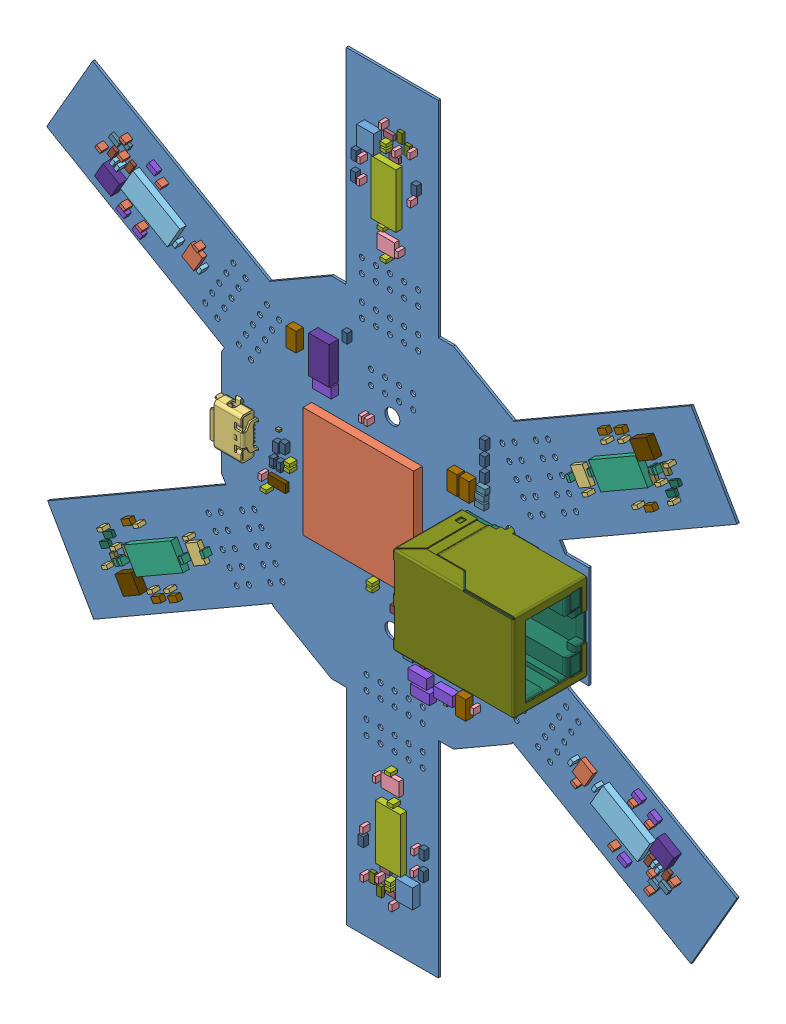
SolidWorks assembly PCB_Testplatine, configuration Standard. Lengths in mm.
Overall size (124.77 137.35 16.55).
543 component instances, 40 part files, 0 mates.
Components (placement in the parent):
- Board-1: Board [Standard] at (0 0 -0.4115) size (124.77 137.35 0.41)
- X_TDA_1_TDA6-1: X_TDA_1_TDA6 [Standard] at origin size (3.77 4.02 0.8)
  - 668293800-1: 668293800 [Standard] at (-35.3942 22.6879 0) size (3.77 4.02 0.8)
    - Extruded-1: Extruded [Standard] at origin size (3.77 4.02 0.8)
- X_TDA_1_TDA5-1: X_TDA_1_TDA5 [Standard] at origin size (3.77 4.02 0.8)
  - 668293664-1: 668293664 [Standard] at (-34.8042 -23.4933 0) size (3.77 4.02 0.8)
    - Extruded_2-1: Extruded_2 [Standard] at origin size (3.77 4.02 0.8)
- X_TDA_1_TDA4-1: X_TDA_1_TDA4 [Standard] at origin size (3.2 2.5 0.8)
  - 668292848-1: 668292848 [Standard] at (0.38 -41.99 0) size (3.2 2.5 0.8)
    - Extruded_3-1: Extruded_3 [Standard] at origin size (3.2 2.5 0.8)
- X_TDA_1_TDA3-1: X_TDA_1_TDA3 [Standard] at origin size (3.77 4.02 0.8)
  - 668293800-1: 668293800 [Standard] at (35.1741 -22.7679 0) size (3.77 4.02 0.8)
    - Extruded-1: Extruded [Standard] at origin size (3.77 4.02 0.8)
- X_TDA_1_TDA2-1: X_TDA_1_TDA2 [Standard] at origin size (3.77 4.02 0.8)
  - 668293664-1: 668293664 [Standard] at (34.8045 23.5121 0) size (3.77 4.02 0.8)
    - Extruded_2-1: Extruded_2 [Standard] at origin size (3.77 4.02 0.8)
- TDA5340_TDA6-1: TDA5340_TDA6 [Standard] at origin size (10.74 8.8 1.15)
  - 668292576-1: 668292576 [Standard] at (-42.5822 26.8379 0.05) size (10.74 8.8 1.15)
    - Extruded_4-1: Extruded_4 [Standard] at origin size (10.74 8.8 1.15)
- TDA5340_TDA5-1: TDA5340_TDA5 [Standard] at origin size (10.74 8.8 1.15)
  - 668292440-1: 668292440 [Standard] at (-41.9922 -27.6432 0.05) size (10.74 8.8 1.15)
    - Extruded_5-1: Extruded_5 [Standard] at origin size (10.74 8.8 1.15)
- TDA5340_TDA4-1: TDA5340_TDA4 [Standard] at origin size (4.5 9.8 1.15)
  - 668289992-1: 668289992 [Standard] at (0.38 -50.29 0.05) size (4.5 9.8 1.15)
    - Extruded_6-1: Extruded_6 [Standard] at origin size (4.5 9.8 1.15)
- TDA5340_TDA3-1: TDA5340_TDA3 [Standard] at origin size (10.74 8.8 1.15)
  - 668292576-1: 668292576 [Standard] at (42.3622 -26.9179 0.05) size (10.74 8.8 1.15)
    - Extruded_4-1: Extruded_4 [Standard] at origin size (10.74 8.8 1.15)
- TDA5340_TDA2-1: TDA5340_TDA2 [Standard] at origin size (10.74 8.8 1.15)
  - 668292440-1: 668292440 [Standard] at (41.9925 27.6621 0.05) size (10.74 8.8 1.15)
    - Extruded_5-1: Extruded_5 [Standard] at origin size (10.74 8.8 1.15)
- R3_TDA6-1: R3_TDA6 [Standard] at origin size (1.95 1.67 0.9)
  - 668292304-1: 668292304 [Standard] at (-42.6285 32.8576 0) size (1.95 1.67 0.9)
    - Extruded_7-1: Extruded_7 [Standard] at origin size (1.95 1.67 0.9)
- R3_TDA5-1: R3_TDA5 [Standard] at origin size (1.95 1.67 0.9)
  - 668292168-1: 668292168 [Standard] at (-47.2285 -24.6736 0) size (1.95 1.67 0.9)
    - Extruded_8-1: Extruded_8 [Standard] at origin size (1.95 1.67 0.9)
- R3_TDA4-1: R3_TDA4 [Standard] at origin size (0.95 1.7 0.9)
  - 668289312-1: 668289312 [Standard] at (-4.81 -53.34 0) size (0.95 1.7 0.9)
    - Extruded_9-1: Extruded_9 [Standard] at origin size (0.95 1.7 0.9)
- R3_TDA3-1: R3_TDA3 [Standard] at origin size (1.95 1.67 0.9)
  - 668292304-1: 668292304 [Standard] at (42.4085 -32.9376 0) size (1.95 1.67 0.9)
    - Extruded_7-1: Extruded_7 [Standard] at origin size (1.95 1.67 0.9)
- R3_TDA2-1: R3_TDA2 [Standard] at origin size (1.95 1.67 0.9)
  - 668292168-1: 668292168 [Standard] at (47.2288 24.6924 0) size (1.95 1.67 0.9)
    - Extruded_8-1: Extruded_8 [Standard] at origin size (1.95 1.67 0.9)
- R2_TDA6-1: R2_TDA6 [Standard] at origin size (1.95 1.67 0.9)
  - 668292304-1: 668292304 [Standard] at (-48.1169 23.4516 0) size (1.95 1.67 0.9)
    - Extruded_7-1: Extruded_7 [Standard] at origin size (1.95 1.67 0.9)
- R2_TDA5-1: R2_TDA5 [Standard] at origin size (1.95 1.67 0.9)
  - 668292168-1: 668292168 [Standard] at (-41.8269 -34.1296 0) size (1.95 1.67 0.9)
    - Extruded_8-1: Extruded_8 [Standard] at origin size (1.95 1.67 0.9)
- R2_TDA4-1: R2_TDA4 [Standard] at origin size (0.95 1.7 0.9)
  - 668289312-1: 668289312 [Standard] at (6.08 -53.39 0) size (0.95 1.7 0.9)
    - Extruded_9-1: Extruded_9 [Standard] at origin size (0.95 1.7 0.9)
- R2_TDA3-1: R2_TDA3 [Standard] at origin size (1.95 1.67 0.9)
  - 668292304-1: 668292304 [Standard] at (47.8969 -23.5316 0) size (1.95 1.67 0.9)
    - Extruded_7-1: Extruded_7 [Standard] at origin size (1.95 1.67 0.9)
- R2_TDA2-1: R2_TDA2 [Standard] at origin size (1.95 1.67 0.9)
  - 668292168-1: 668292168 [Standard] at (41.8271 34.1484 0) size (1.95 1.67 0.9)
    - Extruded_8-1: Extruded_8 [Standard] at origin size (1.95 1.67 0.9)
- R1_TDA6-1: R1_TDA6 [Standard] at origin size (1.95 1.67 0.9)
  - 668292304-1: 668292304 [Standard] at (-45.2224 21.6649 0) size (1.95 1.67 0.9)
    - Extruded_7-1: Extruded_7 [Standard] at origin size (1.95 1.67 0.9)
- R1_TDA5-1: R1_TDA5 [Standard] at origin size (1.95 1.67 0.9)
  - 668292168-1: 668292168 [Standard] at (-38.8324 -32.5162 0) size (1.95 1.67 0.9)
    - Extruded_8-1: Extruded_8 [Standard] at origin size (1.95 1.67 0.9)
- R1_TDA4-1: R1_TDA4 [Standard] at origin size (0.95 1.7 0.9)
  - 668289312-1: 668289312 [Standard] at (6.18 -49.99 0) size (0.95 1.7 0.9)
    - Extruded_9-1: Extruded_9 [Standard] at origin size (0.95 1.7 0.9)
- R1_TDA3-1: R1_TDA3 [Standard] at origin size (1.95 1.67 0.9)
  - 668292304-1: 668292304 [Standard] at (45.0024 -21.7449 0) size (1.95 1.67 0.9)
    - Extruded_7-1: Extruded_7 [Standard] at origin size (1.95 1.67 0.9)
- R1_TDA2-1: R1_TDA2 [Standard] at origin size (1.95 1.67 0.9)
  - 668292168-1: 668292168 [Standard] at (38.8326 32.535 0) size (1.95 1.67 0.9)
    - Extruded_8-1: Extruded_8 [Standard] at origin size (1.95 1.67 0.9)
- L4_TDA6-1: L4_TDA6 [Standard] at origin size (1.7 1.99 0.55)
  - 668291760-1: 668291760 [Standard] at (-50.1898 31.4611 0) size (1.7 1.99 0.55)
    - Extruded_10-1: Extruded_10 [Standard] at origin size (1.7 1.99 0.55)
- L4_TDA5-1: L4_TDA5 [Standard] at origin size (1.7 1.99 0.55)
  - 668291624-1: 668291624 [Standard] at (-49.7998 -31.9201 0) size (1.7 1.99 0.55)
    - Extruded_11-1: Extruded_11 [Standard] at origin size (1.7 1.99 0.55)
- L4_TDA4-1: L4_TDA4 [Standard] at origin size (1.75 0.95 0.55)
  - 668290400-1: 668290400 [Standard] at (0.18 -59.19 0) size (1.75 0.95 0.55)
    - Extruded_12-1: Extruded_12 [Standard] at origin size (1.75 0.95 0.55)
- L4_TDA3-1: L4_TDA3 [Standard] at origin size (1.7 1.99 0.55)
  - 668291760-1: 668291760 [Standard] at (49.9698 -31.5411 0) size (1.7 1.99 0.55)
    - Extruded_10-1: Extruded_10 [Standard] at origin size (1.7 1.99 0.55)
- L4_TDA2-1: L4_TDA2 [Standard] at origin size (1.7 1.99 0.55)
  - 668291624-1: 668291624 [Standard] at (49.8001 31.9389 0) size (1.7 1.99 0.55)
    - Extruded_11-1: Extruded_11 [Standard] at origin size (1.7 1.99 0.55)
- L3_TDA6-1: L3_TDA6 [Standard] at origin size (1.99 1.7 0.55)
  - 668292032-1: 668292032 [Standard] at (-47.8899 34.0246 0) size (1.99 1.7 0.55)
    - Extruded_13-1: Extruded_13 [Standard] at origin size (1.99 1.7 0.55)
- L3_TDA5-1: L3_TDA5 [Standard] at origin size (1.99 1.7 0.55)
  - 668291896-1: 668291896 [Standard] at (-50.8699 -28.6466 0) size (1.99 1.7 0.55)
    - Extruded_14-1: Extruded_14 [Standard] at origin size (1.99 1.7 0.55)
- L3_TDA4-1: L3_TDA4 [Standard] at origin size (0.95 1.75 0.55)
  - 668290536-1: 668290536 [Standard] at (-3.19 -58.48 0) size (0.95 1.75 0.55)
    - Extruded_15-1: Extruded_15 [Standard] at origin size (0.95 1.75 0.55)
- L3_TDA3-1: L3_TDA3 [Standard] at origin size (1.99 1.7 0.55)
  - 668292032-1: 668292032 [Standard] at (47.6699 -34.1046 0) size (1.99 1.7 0.55)
    - Extruded_13-1: Extruded_13 [Standard] at origin size (1.99 1.7 0.55)
- L3_TDA2-1: L3_TDA2 [Standard] at origin size (1.99 1.7 0.55)
  - 668291896-1: 668291896 [Standard] at (50.8702 28.6654 0) size (1.99 1.7 0.55)
    - Extruded_14-1: Extruded_14 [Standard] at origin size (1.99 1.7 0.55)
- L2_TDA6-1: L2_TDA6 [Standard] at origin size (1.99 1.7 0.55)
  - 668292032-1: 668292032 [Standard] at (-49.792 33.6101 0) size (1.99 1.7 0.55)
    - Extruded_13-1: Extruded_13 [Standard] at origin size (1.99 1.7 0.55)
- L2_TDA5-1: L2_TDA5 [Standard] at origin size (1.99 1.7 0.55)
  - 668291896-1: 668291896 [Standard] at (-51.462 -30.5011 0) size (1.99 1.7 0.55)
    - Extruded_14-1: Extruded_14 [Standard] at origin size (1.99 1.7 0.55)
- L2_TDA4-1: L2_TDA4 [Standard] at origin size (0.95 1.75 0.55)
  - 668290536-1: 668290536 [Standard] at (-1.88 -59.92 0) size (0.95 1.75 0.55)
    - Extruded_15-1: Extruded_15 [Standard] at origin size (0.95 1.75 0.55)
- L2_TDA3-1: L2_TDA3 [Standard] at origin size (1.99 1.7 0.55)
  - 668292032-1: 668292032 [Standard] at (49.572 -33.6901 0) size (1.99 1.7 0.55)
    - Extruded_13-1: Extruded_13 [Standard] at origin size (1.99 1.7 0.55)
- L2_TDA2-1: L2_TDA2 [Standard] at origin size (1.99 1.7 0.55)
  - 668291896-1: 668291896 [Standard] at (51.4623 30.5199 0) size (1.99 1.7 0.55)
    - Extruded_14-1: Extruded_14 [Standard] at origin size (1.99 1.7 0.55)
- L1_TDA6-1: L1_TDA6 [Standard] at origin size (1.7 1.99 0.55)
  - 668291760-1: 668291760 [Standard] at (-47.0051 30.7771 0) size (1.7 1.99 0.55)
    - Extruded_10-1: Extruded_10 [Standard] at origin size (1.7 1.99 0.55)
- L1_TDA5-1: L1_TDA5 [Standard] at origin size (1.7 1.99 0.55)
  - 668291624-1: 668291624 [Standard] at (-47.6151 -29.504 0) size (1.7 1.99 0.55)
    - Extruded_11-1: Extruded_11 [Standard] at origin size (1.7 1.99 0.55)
- L1_TDA4-1: L1_TDA4 [Standard] at origin size (1.75 0.95 0.55)
  - 668290400-1: 668290400 [Standard] at (-0.82 -56.09 0) size (1.75 0.95 0.55)
    - Extruded_12-1: Extruded_12 [Standard] at origin size (1.75 0.95 0.55)
- L1_TDA3-1: L1_TDA3 [Standard] at origin size (1.7 1.99 0.55)
  - 668291760-1: 668291760 [Standard] at (46.7851 -30.8571 0) size (1.7 1.99 0.55)
    - Extruded_10-1: Extruded_10 [Standard] at origin size (1.7 1.99 0.55)
- L1_TDA2-1: L1_TDA2 [Standard] at origin size (1.7 1.99 0.55)
  - 668291624-1: 668291624 [Standard] at (47.6154 29.5229 0) size (1.7 1.99 0.55)
    - Extruded_11-1: Extruded_11 [Standard] at origin size (1.7 1.99 0.55)
- F1_TDA6-1: F1_TDA6 [Standard] at origin size (4.54 4.41 1.4)
  - 668293528-1: 668293528 [Standard] at (-50.1943 27.6532 0) size (4.54 4.41 1.4)
    - Extruded_16-1: Extruded_16 [Standard] at origin size (4.54 4.41 1.4)
- F1_TDA5-1: F1_TDA5 [Standard] at origin size (4.54 4.41 1.4)
  - 668293392-1: 668293392 [Standard] at (-46.5044 -33.8279 0) size (4.54 4.41 1.4)
    - Extruded_17-1: Extruded_17 [Standard] at origin size (4.54 4.41 1.4)
- F1_TDA4-1: F1_TDA4 [Standard] at origin size (3.1 3.45 1.4)
  - 668293256-1: 668293256 [Standard] at (3.48 -57.29 0) size (3.1 3.45 1.4)
    - Extruded_18-1: Extruded_18 [Standard] at origin size (3.1 3.45 1.4)
- F1_TDA3-1: F1_TDA3 [Standard] at origin size (4.54 4.41 1.4)
  - 668293528-1: 668293528 [Standard] at (49.9743 -27.7332 0) size (4.54 4.41 1.4)
    - Extruded_16-1: Extruded_16 [Standard] at origin size (4.54 4.41 1.4)
- F1_TDA2-1: F1_TDA2 [Standard] at origin size (4.54 4.41 1.4)
  - 668293392-1: 668293392 [Standard] at (46.5047 33.8467 0) size (4.54 4.41 1.4)
    - Extruded_17-1: Extruded_17 [Standard] at origin size (4.54 4.41 1.4)
- C31_TDA6-1: C31_TDA6 [Standard] at origin size (1.25 1.07 1.3)
  - 668291216-1: 668291216 [Standard] at (-51.8712 31.5889 0) size (1.25 1.07 1.3)
    - Extruded_19-1: Extruded_19 [Standard] at origin size (1.25 1.07 1.3)
- C31_TDA5-1: C31_TDA5 [Standard] at origin size (1.25 1.07 1.3)
  - 668291080-1: 668291080 [Standard] at (-50.7512 -33.3123 0) size (1.25 1.07 1.3)
    - Extruded_20-1: Extruded_20 [Standard] at origin size (1.25 1.07 1.3)
- C31_TDA4-1: C31_TDA4 [Standard] at origin size (0.6 1.1 1.3)
  - 668289448-1: 668289448 [Standard] at (0.91 -60.71 0) size (0.6 1.1 1.3)
    - Extruded_21-1: Extruded_21 [Standard] at origin size (0.6 1.1 1.3)
- C31_TDA3-1: C31_TDA3 [Standard] at origin size (1.25 1.07 1.3)
  - 668291216-1: 668291216 [Standard] at (51.6512 -31.6689 0) size (1.25 1.07 1.3)
    - Extruded_19-1: Extruded_19 [Standard] at origin size (1.25 1.07 1.3)
- C31_TDA2-1: C31_TDA2 [Standard] at origin size (1.25 1.07 1.3)
  - 668291080-1: 668291080 [Standard] at (50.7515 33.3311 0) size (1.25 1.07 1.3)
    - Extruded_20-1: Extruded_20 [Standard] at origin size (1.25 1.07 1.3)
- C30_TDA6-1: C30_TDA6 [Standard] at origin size (1.25 1.07 1.3)
  - 668291216-1: 668291216 [Standard] at (-47.5295 35.0289 0) size (1.25 1.07 1.3)
    - Extruded_19-1: Extruded_19 [Standard] at origin size (1.25 1.07 1.3)
- C30_TDA5-1: C30_TDA5 [Standard] at origin size (1.25 1.07 1.3)
  - 668291080-1: 668291080 [Standard] at (-51.5595 -27.8323 0) size (1.25 1.07 1.3)
    - Extruded_20-1: Extruded_20 [Standard] at origin size (1.25 1.07 1.3)
- C30_TDA4-1: C30_TDA4 [Standard] at origin size (0.6 1.1 1.3)
  - 668289448-1: 668289448 [Standard] at (-4.24 -58.67 0) size (0.6 1.1 1.3)
    - Extruded_21-1: Extruded_21 [Standard] at origin size (0.6 1.1 1.3)
- C30_TDA3-1: C30_TDA3 [Standard] at origin size (1.25 1.07 1.3)
  - 668291216-1: 668291216 [Standard] at (47.3095 -35.1089 0) size (1.25 1.07 1.3)
    - Extruded_19-1: Extruded_19 [Standard] at origin size (1.25 1.07 1.3)
- C30_TDA2-1: C30_TDA2 [Standard] at origin size (1.25 1.07 1.3)
  - 668291080-1: 668291080 [Standard] at (51.5598 27.8511 0) size (1.25 1.07 1.3)
    - Extruded_20-1: Extruded_20 [Standard] at origin size (1.25 1.07 1.3)
- C29_TDA6-1: C29_TDA6 [Standard] at origin size (1.07 1.25 1.3)
  - 668291488-1: 668291488 [Standard] at (-49.3371 30.7379 0) size (1.07 1.25 1.3)
    - Extruded_22-1: Extruded_22 [Standard] at origin size (1.07 1.25 1.3)
- C29_TDA5-1: C29_TDA5 [Standard] at origin size (1.07 1.25 1.3)
  - 668291352-1: 668291352 [Standard] at (-48.7472 -31.5432 0) size (1.07 1.25 1.3)
    - Extruded_23-1: Extruded_23 [Standard] at origin size (1.07 1.25 1.3)
- C29_TDA4-1: C29_TDA4 [Standard] at origin size (1.1 0.6 1.3)
  - 668289176-1: 668289176 [Standard] at (0.38 -58.09 0) size (1.1 0.6 1.3)
    - Extruded_24-1: Extruded_24 [Standard] at origin size (1.1 0.6 1.3)
- C29_TDA3-1: C29_TDA3 [Standard] at origin size (1.07 1.25 1.3)
  - 668291488-1: 668291488 [Standard] at (49.1171 -30.8179 0) size (1.07 1.25 1.3)
    - Extruded_22-1: Extruded_22 [Standard] at origin size (1.07 1.25 1.3)
- C29_TDA2-1: C29_TDA2 [Standard] at origin size (1.07 1.25 1.3)
  - 668291352-1: 668291352 [Standard] at (48.7475 31.5621 0) size (1.07 1.25 1.3)
    - Extruded_23-1: Extruded_23 [Standard] at origin size (1.07 1.25 1.3)
- C28_TDA6-1: C28_TDA6 [Standard] at origin size (1.07 1.25 1.3)
  - 668291488-1: 668291488 [Standard] at (-48.5577 30.2879 0) size (1.07 1.25 1.3)
    - Extruded_22-1: Extruded_22 [Standard] at origin size (1.07 1.25 1.3)
- C28_TDA5-1: C28_TDA5 [Standard] at origin size (1.07 1.25 1.3)
  - 668291352-1: 668291352 [Standard] at (-47.9677 -31.0933 0) size (1.07 1.25 1.3)
    - Extruded_23-1: Extruded_23 [Standard] at origin size (1.07 1.25 1.3)
- C28_TDA4-1: C28_TDA4 [Standard] at origin size (1.1 0.6 1.3)
  - 668289176-1: 668289176 [Standard] at (0.38 -57.19 0) size (1.1 0.6 1.3)
    - Extruded_24-1: Extruded_24 [Standard] at origin size (1.1 0.6 1.3)
- C28_TDA3-1: C28_TDA3 [Standard] at origin size (1.07 1.25 1.3)
  - 668291488-1: 668291488 [Standard] at (48.3377 -30.3679 0) size (1.07 1.25 1.3)
    - Extruded_22-1: Extruded_22 [Standard] at origin size (1.07 1.25 1.3)
- C28_TDA2-1: C28_TDA2 [Standard] at origin size (1.07 1.25 1.3)
  - 668291352-1: 668291352 [Standard] at (47.968 31.1121 0) size (1.07 1.25 1.3)
    - Extruded_23-1: Extruded_23 [Standard] at origin size (1.07 1.25 1.3)
- C27_TDA6-1: C27_TDA6 [Standard] at origin size (1.25 1.07 1.3)
  - 668291216-1: 668291216 [Standard] at (-47.9541 32.1333 0) size (1.25 1.07 1.3)
    - Extruded_19-1: Extruded_19 [Standard] at origin size (1.25 1.07 1.3)
- C27_TDA5-1: C27_TDA5 [Standard] at origin size (1.25 1.07 1.3)
  - 668291080-1: 668291080 [Standard] at (-49.2641 -29.6478 0) size (1.25 1.07 1.3)
    - Extruded_20-1: Extruded_20 [Standard] at origin size (1.25 1.07 1.3)
- C27_TDA4-1: C27_TDA4 [Standard] at origin size (0.6 1.1 1.3)
  - 668289448-1: 668289448 [Standard] at (-1.52 -57.59 0) size (0.6 1.1 1.3)
    - Extruded_21-1: Extruded_21 [Standard] at origin size (0.6 1.1 1.3)
- C27_TDA3-1: C27_TDA3 [Standard] at origin size (1.25 1.07 1.3)
  - 668291216-1: 668291216 [Standard] at (47.7341 -32.2133 0) size (1.25 1.07 1.3)
    - Extruded_19-1: Extruded_19 [Standard] at origin size (1.25 1.07 1.3)
- C27_TDA2-1: C27_TDA2 [Standard] at origin size (1.25 1.07 1.3)
  - 668291080-1: 668291080 [Standard] at (49.2644 29.6666 0) size (1.25 1.07 1.3)
    - Extruded_20-1: Extruded_20 [Standard] at origin size (1.25 1.07 1.3)
- C26_TDA6-1: C26_TDA6 [Standard] at origin size (1.07 1.25 1.3)
  - 668291488-1: 668291488 [Standard] at (-33.6621 21.6879 0) size (1.07 1.25 1.3)
    - Extruded_22-1: Extruded_22 [Standard] at origin size (1.07 1.25 1.3)
- C26_TDA5-1: C26_TDA5 [Standard] at origin size (1.07 1.25 1.3)
  - 668291352-1: 668291352 [Standard] at (-33.0721 -22.4933 0) size (1.07 1.25 1.3)
    - Extruded_23-1: Extruded_23 [Standard] at origin size (1.07 1.25 1.3)
- C26_TDA4-1: C26_TDA4 [Standard] at origin size (1.1 0.6 1.3)
  - 668289176-1: 668289176 [Standard] at (0.38 -39.99 0) size (1.1 0.6 1.3)
    - Extruded_24-1: Extruded_24 [Standard] at origin size (1.1 0.6 1.3)
- C26_TDA3-1: C26_TDA3 [Standard] at origin size (1.07 1.25 1.3)
  - 668291488-1: 668291488 [Standard] at (33.4421 -21.7679 0) size (1.07 1.25 1.3)
    - Extruded_22-1: Extruded_22 [Standard] at origin size (1.07 1.25 1.3)
- C26_TDA2-1: C26_TDA2 [Standard] at origin size (1.07 1.25 1.3)
  - 668291352-1: 668291352 [Standard] at (33.0724 22.5121 0) size (1.07 1.25 1.3)
    - Extruded_23-1: Extruded_23 [Standard] at origin size (1.07 1.25 1.3)
- C25_TDA6-1: C25_TDA6 [Standard] at origin size (1.25 1.07 1.3)
  - 668291216-1: 668291216 [Standard] at (-34.2808 24.8163 0) size (1.25 1.07 1.3)
    - Extruded_19-1: Extruded_19 [Standard] at origin size (1.25 1.07 1.3)
- C25_TDA5-1: C25_TDA5 [Standard] at origin size (1.25 1.07 1.3)
  - 668291080-1: 668291080 [Standard] at (-36.0907 -21.4648 0) size (1.25 1.07 1.3)
    - Extruded_20-1: Extruded_20 [Standard] at origin size (1.25 1.07 1.3)
- C25_TDA4-1: C25_TDA4 [Standard] at origin size (0.6 1.1 1.3)
  - 668289448-1: 668289448 [Standard] at (-2.02 -42.09 0) size (0.6 1.1 1.3)
    - Extruded_21-1: Extruded_21 [Standard] at origin size (0.6 1.1 1.3)
- C25_TDA3-1: C25_TDA3 [Standard] at origin size (1.25 1.07 1.3)
  - 668291216-1: 668291216 [Standard] at (34.0607 -24.8964 0) size (1.25 1.07 1.3)
    - Extruded_19-1: Extruded_19 [Standard] at origin size (1.25 1.07 1.3)
- C25_TDA2-1: C25_TDA2 [Standard] at origin size (1.25 1.07 1.3)
  - 668291080-1: 668291080 [Standard] at (36.091 21.4836 0) size (1.25 1.07 1.3)
    - Extruded_20-1: Extruded_20 [Standard] at origin size (1.25 1.07 1.3)
- C24_TDA6-1: C24_TDA6 [Standard] at origin size (1.07 1.25 1.3)
  - 668291488-1: 668291488 [Standard] at (-37.9824 23.6049 0) size (1.07 1.25 1.3)
    - Extruded_22-1: Extruded_22 [Standard] at origin size (1.07 1.25 1.3)
- C24_TDA5-1: C24_TDA5 [Standard] at origin size (1.07 1.25 1.3)
  - 668291352-1: 668291352 [Standard] at (-36.8924 -25.2763 0) size (1.07 1.25 1.3)
    - Extruded_23-1: Extruded_23 [Standard] at origin size (1.07 1.25 1.3)
- C24_TDA4-1: C24_TDA4 [Standard] at origin size (1.1 0.6 1.3)
  - 668289176-1: 668289176 [Standard] at (0.88 -44.69 0) size (1.1 0.6 1.3)
    - Extruded_24-1: Extruded_24 [Standard] at origin size (1.1 0.6 1.3)
- C24_TDA3-1: C24_TDA3 [Standard] at origin size (1.07 1.25 1.3)
  - 668291488-1: 668291488 [Standard] at (37.7624 -23.6849 0) size (1.07 1.25 1.3)
    - Extruded_22-1: Extruded_22 [Standard] at origin size (1.07 1.25 1.3)
- C24_TDA2-1: C24_TDA2 [Standard] at origin size (1.07 1.25 1.3)
  - 668291352-1: 668291352 [Standard] at (36.8927 25.2951 0) size (1.07 1.25 1.3)
    - Extruded_23-1: Extruded_23 [Standard] at origin size (1.07 1.25 1.3)
- C23_TDA6-1: C23_TDA6 [Standard] at origin size (1.25 1.07 1.3)
  - 668291216-1: 668291216 [Standard] at (-41.0166 31.3495 0) size (1.25 1.07 1.3)
    - Extruded_19-1: Extruded_19 [Standard] at origin size (1.25 1.07 1.3)
- C23_TDA5-1: C23_TDA5 [Standard] at origin size (1.25 1.07 1.3)
  - 668291080-1: 668291080 [Standard] at (-45.1166 -24.0316 0) size (1.25 1.07 1.3)
    - Extruded_20-1: Extruded_20 [Standard] at origin size (1.25 1.07 1.3)
- C23_TDA4-1: C23_TDA4 [Standard] at origin size (0.6 1.1 1.3)
  - 668289448-1: 668289448 [Standard] at (-4.31 -51.19 0) size (0.6 1.1 1.3)
    - Extruded_21-1: Extruded_21 [Standard] at origin size (0.6 1.1 1.3)
- C23_TDA3-1: C23_TDA3 [Standard] at origin size (1.25 1.07 1.3)
  - 668291216-1: 668291216 [Standard] at (40.7966 -31.4296 0) size (1.25 1.07 1.3)
    - Extruded_19-1: Extruded_19 [Standard] at origin size (1.25 1.07 1.3)
- C23_TDA2-1: C23_TDA2 [Standard] at origin size (1.25 1.07 1.3)
  - 668291080-1: 668291080 [Standard] at (45.1169 24.0504 0) size (1.25 1.07 1.3)
    - Extruded_20-1: Extruded_20 [Standard] at origin size (1.25 1.07 1.3)
- C22_TDA6-1: C22_TDA6 [Standard] at origin size (1.25 1.07 1.3)
  - 668291216-1: 668291216 [Standard] at (-47.5534 24.6274 0) size (1.25 1.07 1.3)
    - Extruded_19-1: Extruded_19 [Standard] at origin size (1.25 1.07 1.3)
- C22_TDA5-1: C22_TDA5 [Standard] at origin size (1.25 1.07 1.3)
  - 668291080-1: 668291080 [Standard] at (-42.5634 -33.0538 0) size (1.25 1.07 1.3)
    - Extruded_20-1: Extruded_20 [Standard] at origin size (1.25 1.07 1.3)
- C22_TDA4-1: C22_TDA4 [Standard] at origin size (0.6 1.1 1.3)
  - 668289448-1: 668289448 [Standard] at (4.78 -53.49 0) size (0.6 1.1 1.3)
    - Extruded_21-1: Extruded_21 [Standard] at origin size (0.6 1.1 1.3)
- C22_TDA3-1: C22_TDA3 [Standard] at origin size (1.25 1.07 1.3)
  - 668291216-1: 668291216 [Standard] at (47.3334 -24.7074 0) size (1.25 1.07 1.3)
    - Extruded_19-1: Extruded_19 [Standard] at origin size (1.25 1.07 1.3)
- C22_TDA2-1: C22_TDA2 [Standard] at origin size (1.25 1.07 1.3)
  - 668291080-1: 668291080 [Standard] at (42.5637 33.0726 0) size (1.25 1.07 1.3)
    - Extruded_20-1: Extruded_20 [Standard] at origin size (1.25 1.07 1.3)
- C21_TDA6-1: C21_TDA6 [Standard] at origin size (1.25 1.07 1.3)
  - 668291216-1: 668291216 [Standard] at (-44.5724 22.7908 0) size (1.25 1.07 1.3)
    - Extruded_19-1: Extruded_19 [Standard] at origin size (1.25 1.07 1.3)
- C21_TDA5-1: C21_TDA5 [Standard] at origin size (1.25 1.07 1.3)
  - 668291080-1: 668291080 [Standard] at (-39.4823 -31.3904 0) size (1.25 1.07 1.3)
    - Extruded_20-1: Extruded_20 [Standard] at origin size (1.25 1.07 1.3)
- C21_TDA4-1: C21_TDA4 [Standard] at origin size (0.6 1.1 1.3)
  - 668289448-1: 668289448 [Standard] at (4.88 -49.99 0) size (0.6 1.1 1.3)
    - Extruded_21-1: Extruded_21 [Standard] at origin size (0.6 1.1 1.3)
- C21_TDA3-1: C21_TDA3 [Standard] at origin size (1.25 1.07 1.3)
  - 668291216-1: 668291216 [Standard] at (44.3524 -22.8708 0) size (1.25 1.07 1.3)
    - Extruded_19-1: Extruded_19 [Standard] at origin size (1.25 1.07 1.3)
- C21_TDA2-1: C21_TDA2 [Standard] at origin size (1.25 1.07 1.3)
  - 668291080-1: 668291080 [Standard] at (39.4826 31.4092 0) size (1.25 1.07 1.3)
    - Extruded_20-1: Extruded_20 [Standard] at origin size (1.25 1.07 1.3)
- C1-1: C1 [Standard] at origin size (0.6 1.1 1.3)
  - 668289448-1: 668289448 [Standard] at (-3.55 13 0) size (0.6 1.1 1.3)
    - Extruded_21-1: Extruded_21 [Standard] at origin size (0.6 1.1 1.3)
- C2-1: C2 [Standard] at origin size (1.1 0.6 1.3)
  - 668289176-1: 668289176 [Standard] at (8.85 -4.7 0) size (1.1 0.6 1.3)
    - Extruded_24-1: Extruded_24 [Standard] at origin size (1.1 0.6 1.3)
- C3-1: C3 [Standard] at origin size (1.1 0.6 1.3)
  - 668289176-1: 668289176 [Standard] at (-2.9 -11.95 0) size (1.1 0.6 1.3)
    - Extruded_24-1: Extruded_24 [Standard] at origin size (1.1 0.6 1.3)
- C4-1: C4 [Standard] at origin size (1.1 0.6 1.3)
  - 668289176-1: 668289176 [Standard] at (-17.8 -1.6 0) size (1.1 0.6 1.3)
    - Extruded_24-1: Extruded_24 [Standard] at origin size (1.1 0.6 1.3)
- C5-1: C5 [Standard] at origin size (1.1 0.6 1.3)
  - 668289176-1: 668289176 [Standard] at (-17.8 -0.7 0) size (1.1 0.6 1.3)
    - Extruded_24-1: Extruded_24 [Standard] at origin size (1.1 0.6 1.3)
- C6-1: C6 [Standard] at origin size (1.1 0.6 1.3)
  - 668289176-1: 668289176 [Standard] at (-2.9 -12.85 0) size (1.1 0.6 1.3)
    - Extruded_24-1: Extruded_24 [Standard] at origin size (1.1 0.6 1.3)
- C7-1: C7 [Standard] at origin size (0.6 1.1 1.3)
  - 668289448-1: 668289448 [Standard] at (7.5 -2.9 0) size (0.6 1.1 1.3)
    - Extruded_21-1: Extruded_21 [Standard] at origin size (0.6 1.1 1.3)
- C8-1: C8 [Standard] at origin size (0.6 1.1 1.3)
  - 668289448-1: 668289448 [Standard] at (-4.55 13 0) size (0.6 1.1 1.3)
    - Extruded_21-1: Extruded_21 [Standard] at origin size (0.6 1.1 1.3)
- C9-1: C9 [Standard] at origin size (1.1 0.6 1.3)
  - 668289176-1: 668289176 [Standard] at (10.65 -3.45 0) size (1.1 0.6 1.3)
    - Extruded_24-1: Extruded_24 [Standard] at origin size (1.1 0.6 1.3)
- C10-1: C10 [Standard] at origin size (1.1 0.6 1.3)
  - 668289176-1: 668289176 [Standard] at (9.75 0.55 0) size (1.1 0.6 1.3)
    - Extruded_24-1: Extruded_24 [Standard] at origin size (1.1 0.6 1.3)
- C11-1: C11 [Standard] at origin size (0.6 1.1 1.3)
  - 668289448-1: 668289448 [Standard] at (-22.66 -5.13 0) size (0.6 1.1 1.3)
    - Extruded_21-1: Extruded_21 [Standard] at origin size (0.6 1.1 1.3)
- C12-1: C12 [Standard] at origin size (1.1 0.6 1.3)
  - 668289176-1: 668289176 [Standard] at (-22.06 -6.91 0) size (1.1 0.6 1.3)
    - Extruded_24-1: Extruded_24 [Standard] at origin size (1.1 0.6 1.3)
- C21_TDA1-1: C21_TDA1 [Standard] at origin size (0.6 1.1 1.3)
  - 668289448-1: 668289448 [Standard] at (-4.92 49.94 0) size (0.6 1.1 1.3)
    - Extruded_21-1: Extruded_21 [Standard] at origin size (0.6 1.1 1.3)
- C22_TDA1-1: C22_TDA1 [Standard] at origin size (0.6 1.1 1.3)
  - 668289448-1: 668289448 [Standard] at (-4.82 53.44 0) size (0.6 1.1 1.3)
    - Extruded_21-1: Extruded_21 [Standard] at origin size (0.6 1.1 1.3)
- C23_TDA1-1: C23_TDA1 [Standard] at origin size (0.6 1.1 1.3)
  - 668289448-1: 668289448 [Standard] at (4.27 51.14 0) size (0.6 1.1 1.3)
    - Extruded_21-1: Extruded_21 [Standard] at origin size (0.6 1.1 1.3)
- C24_TDA1-1: C24_TDA1 [Standard] at origin size (1.1 0.6 1.3)
  - 668289176-1: 668289176 [Standard] at (-0.92 44.64 0) size (1.1 0.6 1.3)
    - Extruded_24-1: Extruded_24 [Standard] at origin size (1.1 0.6 1.3)
- C25_TDA1-1: C25_TDA1 [Standard] at origin size (0.6 1.1 1.3)
  - 668289448-1: 668289448 [Standard] at (1.98 42.04 0) size (0.6 1.1 1.3)
    - Extruded_21-1: Extruded_21 [Standard] at origin size (0.6 1.1 1.3)
- C26_TDA1-1: C26_TDA1 [Standard] at origin size (1.1 0.6 1.3)
  - 668289176-1: 668289176 [Standard] at (-0.42 39.94 0) size (1.1 0.6 1.3)
    - Extruded_24-1: Extruded_24 [Standard] at origin size (1.1 0.6 1.3)
- C27_TDA1-1: C27_TDA1 [Standard] at origin size (0.6 1.1 1.3)
  - 668289448-1: 668289448 [Standard] at (1.48 57.54 0) size (0.6 1.1 1.3)
    - Extruded_21-1: Extruded_21 [Standard] at origin size (0.6 1.1 1.3)
- C28_TDA1-1: C28_TDA1 [Standard] at origin size (1.1 0.6 1.3)
  - 668289176-1: 668289176 [Standard] at (-0.42 57.14 0) size (1.1 0.6 1.3)
    - Extruded_24-1: Extruded_24 [Standard] at origin size (1.1 0.6 1.3)
- C29_TDA1-1: C29_TDA1 [Standard] at origin size (1.1 0.6 1.3)
  - 668289176-1: 668289176 [Standard] at (-0.42 58.04 0) size (1.1 0.6 1.3)
    - Extruded_24-1: Extruded_24 [Standard] at origin size (1.1 0.6 1.3)
- C30_TDA1-1: C30_TDA1 [Standard] at origin size (0.6 1.1 1.3)
  - 668289448-1: 668289448 [Standard] at (4.2 58.62 0) size (0.6 1.1 1.3)
    - Extruded_21-1: Extruded_21 [Standard] at origin size (0.6 1.1 1.3)
- C31_TDA1-1: C31_TDA1 [Standard] at origin size (0.6 1.1 1.3)
  - 668289448-1: 668289448 [Standard] at (-0.95 60.66 0) size (0.6 1.1 1.3)
    - Extruded_21-1: Extruded_21 [Standard] at origin size (0.6 1.1 1.3)
- C100-1: C100 [Standard] at origin size (3.4 1.8 1.3)
  - 668290944-1: 668290944 [Standard] at (-11.45 14.43 0) size (3.4 1.8 1.3)
    - Extruded_25-1: Extruded_25 [Standard] at origin size (3.4 1.8 1.3)
- C101-1: C101 [Standard] at origin size (1.8 3.4 1.3)
  - 668290808-1: 668290808 [Standard] at (-17 19.25 0) size (1.8 3.4 1.3)
    - Extruded_26-1: Extruded_26 [Standard] at origin size (1.8 3.4 1.3)
- C200-1: C200 [Standard] at origin size (0.6 1.1 1.3)
  - 668289448-1: 668289448 [Standard] at (7.55 -11.75 0) size (0.6 1.1 1.3)
    - Extruded_21-1: Extruded_21 [Standard] at origin size (0.6 1.1 1.3)
- C201-1: C201 [Standard] at origin size (0.6 1.1 1.3)
  - 668289448-1: 668289448 [Standard] at (15.65 -22.65 0) size (0.6 1.1 1.3)
    - Extruded_21-1: Extruded_21 [Standard] at origin size (0.6 1.1 1.3)
- C202-1: C202 [Standard] at origin size (3.4 1.8 1.3)
  - 668290944-1: 668290944 [Standard] at (6.3 -24.7 0) size (3.4 1.8 1.3)
    - Extruded_25-1: Extruded_25 [Standard] at origin size (3.4 1.8 1.3)
- C203-1: C203 [Standard] at origin size (1.8 3.4 1.3)
  - 668290808-1: 668290808 [Standard] at (12.1 11.35 0) size (1.8 3.4 1.3)
    - Extruded_26-1: Extruded_26 [Standard] at origin size (1.8 3.4 1.3)
- C204-1: C204 [Standard] at origin size (1.8 3.4 1.3)
  - 668290808-1: 668290808 [Standard] at (14.25 11.35 0) size (1.8 3.4 1.3)
    - Extruded_26-1: Extruded_26 [Standard] at origin size (1.8 3.4 1.3)
- C205-1: C205 [Standard] at origin size (0.6 1.1 1.3)
  - 668289448-1: 668289448 [Standard] at (13.15 -17.5 0) size (0.6 1.1 1.3)
    - Extruded_21-1: Extruded_21 [Standard] at origin size (0.6 1.1 1.3)
- C206-1: C206 [Standard] at origin size (1.1 0.6 1.3)
  - 668289176-1: 668289176 [Standard] at (15.1 -13.45 0) size (1.1 0.6 1.3)
    - Extruded_24-1: Extruded_24 [Standard] at origin size (1.1 0.6 1.3)
- C207-1: C207 [Standard] at origin size (3.4 1.8 1.3)
  - 668290944-1: 668290944 [Standard] at (10.45 -22.95 0) size (3.4 1.8 1.3)
    - Extruded_25-1: Extruded_25 [Standard] at origin size (3.4 1.8 1.3)
- C208-1: C208 [Standard] at origin size (1.8 3.4 1.3)
  - 668290808-1: 668290808 [Standard] at (13.65 -23.05 0) size (1.8 3.4 1.3)
    - Extruded_26-1: Extruded_26 [Standard] at origin size (1.8 3.4 1.3)
- C209-1: C209 [Standard] at origin size (3.4 1.8 1.3)
  - 668290944-1: 668290944 [Standard] at (5.8 -22.55 0) size (3.4 1.8 1.3)
    - Extruded_25-1: Extruded_25 [Standard] at origin size (3.4 1.8 1.3)
- C210-1: C210 [Standard] at origin size (1.8 3.4 1.3)
  - 668290808-1: 668290808 [Standard] at (2.93 -17.7 0) size (1.8 3.4 1.3)
    - Extruded_26-1: Extruded_26 [Standard] at origin size (1.8 3.4 1.3)
- D2-1: D2 [Standard] at origin size (0.8 1.6 0.9)
  - WE-VE_0603-1: WE-VE_0603 [Standard] at (-19.7501 -2.2499 0.42) x (1 0 0) z (0 0 1) size (0.8 1.6 0.9)
- D3-1: D3 [Standard] at origin size (0.8 1.6 0.9)
  - WE-VE_0603-1: WE-VE_0603 [Standard] at (-21.0001 -2.2499 0.42) x (1 0 0) z (0 0 1) size (0.8 1.6 0.9)
- D200-1: D200 [Standard] at origin size (0.8 1.2 0.59)
  - 668290672-1: 668290672 [Standard] at (0.55 -14.6032 0) size (0.8 1.2 0.59)
    - Extruded_27-1: Extruded_27 [Standard] at origin size (0.8 1.2 0.59)
- D201-1: D201 [Standard] at origin size (0.8 1.2 0.59)
  - 668290672-1: 668290672 [Standard] at (6 -20.4968 0) size (0.8 1.2 0.59)
    - Extruded_27-1: Extruded_27 [Standard] at origin size (0.8 1.2 0.59)
- F1_TDA1-1: F1_TDA1 [Standard] at origin size (3.1 3.45 1.4)
  - 668293256-1: 668293256 [Standard] at (-3.52 57.24 0) size (3.1 3.45 1.4)
    - Extruded_18-1: Extruded_18 [Standard] at origin size (3.1 3.45 1.4)
- L1_TDA1-1: L1_TDA1 [Standard] at origin size (1.75 0.95 0.55)
  - 668290400-1: 668290400 [Standard] at (0.78 56.04 0) size (1.75 0.95 0.55)
    - Extruded_12-1: Extruded_12 [Standard] at origin size (1.75 0.95 0.55)
- L2_TDA1-1: L2_TDA1 [Standard] at origin size (0.95 1.75 0.55)
  - 668290536-1: 668290536 [Standard] at (1.84 59.87 0) size (0.95 1.75 0.55)
    - Extruded_15-1: Extruded_15 [Standard] at origin size (0.95 1.75 0.55)
- L3_TDA1-1: L3_TDA1 [Standard] at origin size (0.95 1.75 0.55)
  - 668290536-1: 668290536 [Standard] at (3.15 58.43 0) size (0.95 1.75 0.55)
    - Extruded_15-1: Extruded_15 [Standard] at origin size (0.95 1.75 0.55)
- L4_TDA1-1: L4_TDA1 [Standard] at origin size (1.75 0.95 0.55)
  - 668290400-1: 668290400 [Standard] at (-0.22 59.14 0) size (1.75 0.95 0.55)
    - Extruded_12-1: Extruded_12 [Standard] at origin size (1.75 0.95 0.55)
- L11-1: L11 [Standard] at origin size (0.65 0.35 0.55)
  - 668290264-1: 668290264 [Standard] at (-20.25 3 0) size (0.65 0.35 0.55)
    - Extruded_28-1: Extruded_28 [Standard] at origin size (0.65 0.35 0.55)
- L200-1: L200 [Standard] at origin size (0.65 0.35 0.55)
  - 668290264-1: 668290264 [Standard] at (10.1 -24.75 0) size (0.65 0.35 0.55)
    - Extruded_28-1: Extruded_28 [Standard] at origin size (0.65 0.35 0.55)
- L201-1: L201 [Standard] at origin size (0.35 0.65 0.55)
  - 668290128-1: 668290128 [Standard] at (10.65 10.9 0) size (0.35 0.65 0.55)
    - Extruded_29-1: Extruded_29 [Standard] at origin size (0.35 0.65 0.55)
- R1_TDA1-1: R1_TDA1 [Standard] at origin size (0.95 1.7 0.9)
  - 668289312-1: 668289312 [Standard] at (-6.22 49.94 0) size (0.95 1.7 0.9)
    - Extruded_9-1: Extruded_9 [Standard] at origin size (0.95 1.7 0.9)
- R2_TDA1-1: R2_TDA1 [Standard] at origin size (0.95 1.7 0.9)
  - 668289312-1: 668289312 [Standard] at (-6.12 53.34 0) size (0.95 1.7 0.9)
    - Extruded_9-1: Extruded_9 [Standard] at origin size (0.95 1.7 0.9)
- R3_TDA1-1: R3_TDA1 [Standard] at origin size (0.95 1.7 0.9)
  - 668289312-1: 668289312 [Standard] at (4.77 53.29 0) size (0.95 1.7 0.9)
    - Extruded_9-1: Extruded_9 [Standard] at origin size (0.95 1.7 0.9)
- R10-1: R10 [Standard] at origin size (0.95 1.7 0.9)
  - 668289312-1: 668289312 [Standard] at (7.95 -0.3 0) size (0.95 1.7 0.9)
    - Extruded_9-1: Extruded_9 [Standard] at origin size (0.95 1.7 0.9)
- R11-1: R11 [Standard] at origin size (0.95 1.7 0.9)
  - 668289312-1: 668289312 [Standard] at (-7.75 24 0) size (0.95 1.7 0.9)
    - Extruded_9-1: Extruded_9 [Standard] at origin size (0.95 1.7 0.9)
- R12-1: R12 [Standard] at origin size (0.95 1.7 0.9)
  - 668289312-1: 668289312 [Standard] at (-19 1 0) size (0.95 1.7 0.9)
    - Extruded_9-1: Extruded_9 [Standard] at origin size (0.95 1.7 0.9)
- R13-1: R13 [Standard] at origin size (0.95 1.7 0.9)
  - 668289312-1: 668289312 [Standard] at (-20.25 0.5 0) size (0.95 1.7 0.9)
    - Extruded_9-1: Extruded_9 [Standard] at origin size (0.95 1.7 0.9)
- R200-1: R200 [Standard] at origin size (1.7 0.95 0.9)
  - 668289584-1: 668289584 [Standard] at (16.61 11.12 0) size (1.7 0.95 0.9)
    - Extruded_30-1: Extruded_30 [Standard] at origin size (1.7 0.95 0.9)
- R201-1: R201 [Standard] at origin size (1.7 0.95 0.9)
  - 668289584-1: 668289584 [Standard] at (16.61 9.87 0) size (1.7 0.95 0.9)
    - Extruded_30-1: Extruded_30 [Standard] at origin size (1.7 0.95 0.9)
- R202-1: R202 [Standard] at origin size (1.7 0.95 0.9)
  - 668289584-1: 668289584 [Standard] at (3.65 -20.4 0) size (1.7 0.95 0.9)
    - Extruded_30-1: Extruded_30 [Standard] at origin size (1.7 0.95 0.9)
- R203-1: R203 [Standard] at origin size (0.95 1.7 0.9)
  - 668289312-1: 668289312 [Standard] at (6.1 -13 0) size (0.95 1.7 0.9)
    - Extruded_9-1: Extruded_9 [Standard] at origin size (0.95 1.7 0.9)
- R204-1: R204 [Standard] at origin size (1.7 0.95 0.9)
  - 668289584-1: 668289584 [Standard] at (12.1 -11.4 0) size (1.7 0.95 0.9)
    - Extruded_30-1: Extruded_30 [Standard] at origin size (1.7 0.95 0.9)
- R205-1: R205 [Standard] at origin size (0.95 1.7 0.9)
  - 668289312-1: 668289312 [Standard] at (12.9 -14.2 0) size (0.95 1.7 0.9)
    - Extruded_9-1: Extruded_9 [Standard] at origin size (0.95 1.7 0.9)
- R206-1: R206 [Standard] at origin size (0.95 1.7 0.9)
  - 668289312-1: 668289312 [Standard] at (4.85 -13 0) size (0.95 1.7 0.9)
    - Extruded_9-1: Extruded_9 [Standard] at origin size (0.95 1.7 0.9)
- T1-1: T1 [Standard] at origin size (21.84 15.88 16.55)
  - 7499010211A-1: 7499010211A [Standard] at (24.4001 -0.1251 6.7) x (0 -1 0) z (0 0 -1) size (15.88 21.84 16.55)
    - housing-1: housing [Standard] at origin size (15.48 21.44 16.35)
    - shielding-1: shielding [Standard] at origin size (15.88 21.84 16.25)
- TDA5340_TDA1-1: TDA5340_TDA1 [Standard] at origin size (4.5 9.8 1.15)
  - 668289992-1: 668289992 [Standard] at (-0.42 50.24 0.05) size (4.5 9.8 1.15)
    - Extruded_6-1: Extruded_6 [Standard] at origin size (4.5 9.8 1.15)
- U1-1: U1 [Standard] at origin size (3.7 6.7 1.7)
  - 668289856-1: 668289856 [Standard] at (-11.5 19 0.1) size (3.7 6.7 1.7)
    - Extruded_31-1: Extruded_31 [Standard] at origin size (3.7 6.7 1.7)
- X1-1: X1 [Standard] at origin size (3.2 2.5 0.8)
  - 668292848-1: 668292848 [Standard] at (10.5 -1.45 0) size (3.2 2.5 0.8)
    - Extruded_3-1: Extruded_3 [Standard] at origin size (3.2 2.5 0.8)
- X2-1: X2 [Standard] at origin size (3.2 1.5 0.65)
  - 668292712-1: 668292712 [Standard] at (-20.27 -5.32 0) size (3.2 1.5 0.65)
    - Extruded_32-1: Extruded_32 [Standard] at origin size (3.2 1.5 0.65)
- X3-1: X3 [Standard] at origin size (2.5 3.2 0.8)
  - 668293120-1: 668293120 [Standard] at (15.2 -15.95 0) size (2.5 3.2 0.8)
    - Extruded_33-1: Extruded_33 [Standard] at origin size (2.5 3.2 0.8)
- X_TDA_1_TDA1-1: X_TDA_1_TDA1 [Standard] at origin size (3.2 2.5 0.8)
  - 668292848-1: 668292848 [Standard] at (-0.42 41.94 0) size (3.2 2.5 0.8)
    - Extruded_3-1: Extruded_3 [Standard] at origin size (3.2 2.5 0.8)
- XMC4500-1: XMC4500 [Standard] at origin size (20 20 1.55)
  - 668289720-1: 668289720 [Standard] at (-4.55 0 0.05) size (20 20 1.55)
    - Extruded_34-1: Extruded_34 [Standard] at origin size (20 20 1.55)
- J1-1: J1 [Standard] at origin size (5.9 8.66 3.36)
  - 475900001-1: 475900001 [Standard] at (-26.2999 1.3001 0.26) x (0 1 0) z (1 0 0) size (8.66 3.36 5.9)
    - Open CASCADE STEP translator 6.8 2.177.1.1-1: Open CASCADE STEP translator 6.8 2.177.1.1 [Standard] at origin size (8.66 3.36 5.9)
- IC3-1: IC3 [Standard] at origin size (4 4 0.85)
  - 668292984-1: 668292984 [Standard] at (8.35 -16.75 0) size (4 4 0.85)
    - Extruded_35-1: Extruded_35 [Standard] at origin size (4 4 0.85)
- R20-1: R20 [Standard] at origin size (1.7 0.95 0.9)
  - 668289584-1: 668289584 [Standard] at (16.83 12.38 0) size (1.7 0.95 0.9)
    - Extruded_30-1: Extruded_30 [Standard] at origin size (1.7 0.95 0.9)
- R21-1: R21 [Standard] at origin size (0.95 1.7 0.9)
  - 668289312-1: 668289312 [Standard] at (17.12 14.47 0) size (0.95 1.7 0.9)
    - Extruded_9-1: Extruded_9 [Standard] at origin size (0.95 1.7 0.9)
- R22-1: R22 [Standard] at origin size (0.95 1.7 0.9)
  - 668289312-1: 668289312 [Standard] at (17.12 17.07 0) size (0.95 1.7 0.9)
    - Extruded_9-1: Extruded_9 [Standard] at origin size (0.95 1.7 0.9)
- R23-1: R23 [Standard] at origin size (0.95 1.7 0.9)
  - 668289312-1: 668289312 [Standard] at (17.14 19.62 0) size (0.95 1.7 0.9)
    - Extruded_9-1: Extruded_9 [Standard] at origin size (0.95 1.7 0.9)
